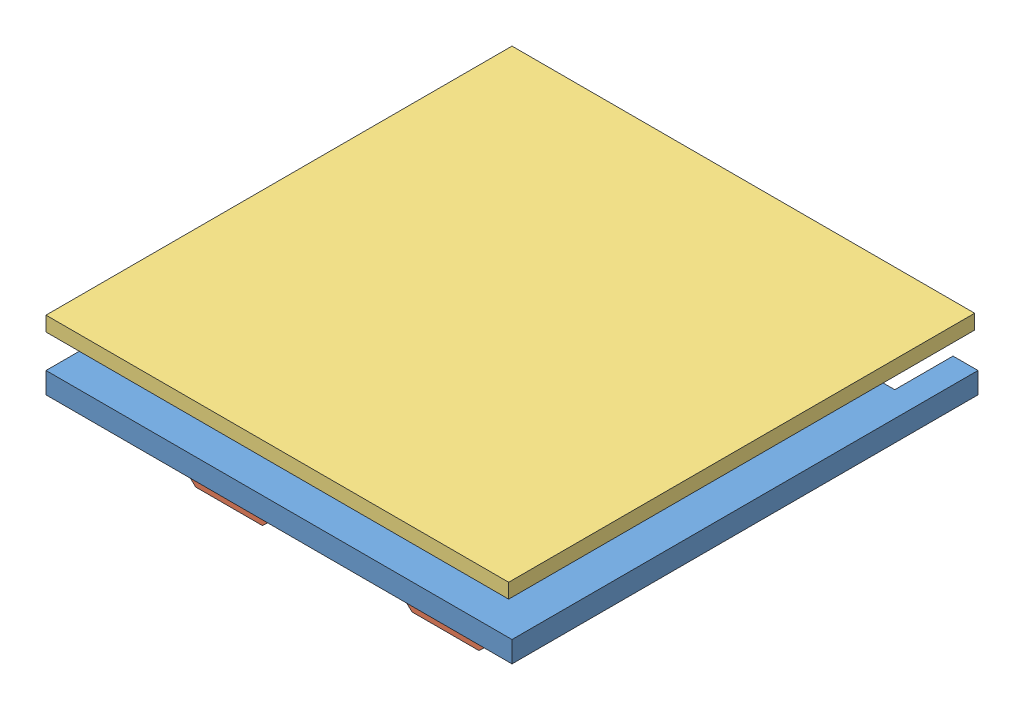
SolidWorks assembly _bedSmallAssem, configuration Default. Lengths in mm.
Overall size (140 39.8 140).
3 component instances, 3 part files, 6 mates.
Components (placement in the parent):
- 140mmZBoard-1: 140mmZBoard [Default] at (-51.0263 75.4967 211.2864) size (140 6.35 140)
- printPlateHolder_V2-1: printPlateHolder_V2 [Default] at (113.9737 75.4967 151.2864) x (-1 0 0) z (0 0 1) size (105.1 19.05 105.1)
- 140mmHotBed-1: 140mmHotBed [Default] at (-8.5263 91.8467 168.7864) size (139 4.4 140)
Mates (geometry in assembly coordinates):
- Coincident1: coincident anti-aligned: plane of 140mmZBoard-1 through (-51.0263 75.4967 211.2864) normal (0 -1 0); plane of printPlateHolder_V2-1 through (113.9737 75.4967 151.2864) normal (0 1 0)
- Concentric1: concentric aligned: cylinder of 140mmZBoard-1 through (69.1737 -22.9107 120.7864) axis (0 1 0) radius 2.6; cylinder of printPlateHolder_V2-1 through (69.1737 65.8599 120.7864) axis (0 1 0) radius 2.7
- Concentric2: concentric anti-aligned: cylinder of 140mmZBoard-1 through (53.7737 -22.9107 120.7864) axis (0 1 0) radius 2.6; circle of printPlateHolder_V2-1
- Distance1: distance = 10 mm anti-aligned: plane of 140mmHotBed-1 through (-8.5263 91.8467 168.7864) normal (0 -1 0); plane of 140mmZBoard-1 through (-51.0263 81.8467 211.2864) normal (0 1 0)
- Coincident3: coincident aligned: plane of 140mmZBoard-1 through (131.4737 -242.7014 168.7864) normal (0 0 1); plane of 140mmHotBed-1 through (-8.5263 96.2467 168.7864) normal (0 0 1)
- Coincident4: coincident aligned: plane of 140mmZBoard-1 through (-8.5263 -242.7014 168.7864) normal (-1 0 0); plane of 140mmHotBed-1 through (-8.5263 96.2467 168.7864) normal (-1 0 0)
